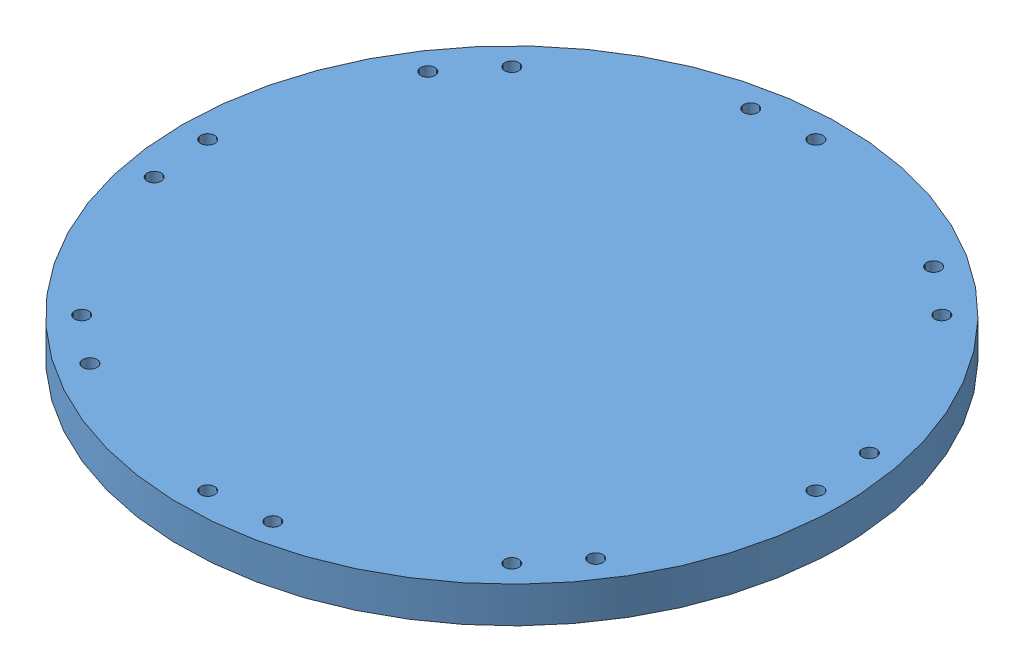
SolidWorks assembly front hub spun, configuration Default. Lengths in mm.
Overall size (232 12.7 232).
2 component instances, 2 part files, 4 mates.
Components (placement in the parent):
- spun wheel-1: spun wheel [Default] at origin (suppressed, hidden)
- frunt hub spun wheel^front hub spun-1: frunt hub spun wheel^front hub spun [Default] at (0 -45.0065 0) x (1 0 0) z (0 1 0) size (232 232 12.7) (virtual)
Mates (geometry in assembly coordinates):
- InPlace1: in place: plane of spun wheel-1 through (-116.0972 -45.0065 0) normal (0 1 0); plane of frunt hub spun wheel^front hub spun-1 through (0 -45.0065 0) normal (0 1 0); moOrthogonalPlaneRef_w of spun wheel-1 through (-116.0972 -45.0065 0) normal (0 1 0); plane of frunt hub spun wheel^front hub spun-1 through (0 -45.0065 0) normal (0 0 -1); plane of spun wheel-1 through (-116.0972 -45.0065 0) normal (0 1 0); plane of frunt hub spun wheel^front hub spun-1 through (0 -45.0065 0) normal (1 0 0); plane of spun wheel-1 through (-116.0972 -45.0065 0) normal (0 1 0); unknown of frunt hub spun wheel^front hub spun-1
- Coincident1: coincident aligned: plane of ?; plane of ?
- Coincident2: coincident aligned: moOrthogonalPlaneRef_w of spun wheel-1 through (0 -45.0065 0) normal (0 0 -1); plane of Part2^Assem2-1 through (0 -45.0065 0) normal (0 0 -1)
- Coincident3: coincident anti-aligned: moOrthogonalPlaneRef_w of spun wheel-1 through (0 -45.0065 0) normal (-1 0 0); plane of Part2^Assem2-1 through (0 -45.0065 0) normal (1 0 0)
